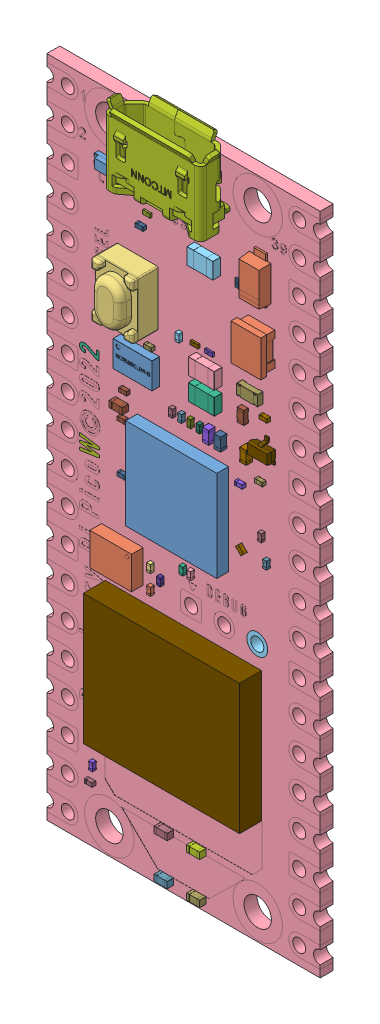
SolidWorks assembly RaspBerryPi Pico W, configuration Default. Lengths in mm.
Overall size (21 52.34 3.69).
82 component instances, 79 part files, 0 mates.
Components (placement in the parent):
- RaspBerryPi Pico W.step-1: RaspBerryPi Pico W.step [Default] at origin size (21 52.34 3.69)
  - PicoW v1.step-1: PicoW v1.step [Default] at (-10.5 -51 1.6) size (14.61 51.8 3.49)
    - Symbols.step-1: Symbols.step [Default] at origin size (14.61 51.8 3.49)
      - AVAGO_QSM.step-1: AVAGO_QSM.step [Default] at origin size (1.65 0.72 0.68)
      - BOURNS_SRN2512.step-1: BOURNS_SRN2512.step [Default] at origin size (2.29 2.79 1.22)
      - CAPC0603.step-1: CAPC0603.step [Default] at origin size (0.3 0.6 0.3)
      - CAPC0603 (1).step-1: CAPC0603 (1).step [Default] at origin size (0.6 0.3 0.3)
      - CAPC0603 (2).step-1: CAPC0603 (2).step [Default] at origin size (0.6 0.3 0.3)
      - CAPC0603 (3).step-1: CAPC0603 (3).step [Default] at origin size (0.6 0.3 0.3)
      - CAPC1005.step-1: CAPC1005.step [Default] at origin size (1 0.5 0.5)
      - CAPC1005 (1).step-1: CAPC1005 (1).step [Default] at origin size (0.5 1 0.5)
      - CAPC1005 (2).step-1: CAPC1005 (2).step [Default] at origin size (0.5 1 0.5)
      - CAPC1005 (3).step-1: CAPC1005 (3).step [Default] at origin size (0.5 1 0.5)
      - CAPC1005 (4).step-1: CAPC1005 (4).step [Default] at origin size (1 0.5 0.5)
      - CAPC1005 (5).step-1: CAPC1005 (5).step [Default] at origin size (1 0.5 0.5)
      - CAPC1005 (6).step-1: CAPC1005 (6).step [Default] at origin size (1 0.5 0.5)
      - CAPC1005 (7).step-1: CAPC1005 (7).step [Default] at origin size (1 0.5 0.5)
      - CAPC1005 (8).step-1: CAPC1005 (8).step [Default] at origin size (0.5 1 0.5)
      - CAPC1005 (9).step-1: CAPC1005 (9).step [Default] at origin size (1 0.5 0.5)
      - CAPC1005X55N.step-1: CAPC1005X55N.step [Default] at origin size (1 0.5 0.5)
      - CAPC1005X55N (1).step-1: CAPC1005X55N (1).step [Default] at origin size (0.5 1 0.5)
      - CAPC1005X55N (2).step-1: CAPC1005X55N (2).step [Default] at origin size (1 0.5 0.5)
      - CAPC1608X90N.step-1: CAPC1608X90N.step [Default] at origin size (1.6 0.8 0.8)
      - CAPC1608X90N (1).step-1: CAPC1608X90N (1).step [Default] at origin size (0.8 1.6 0.8)
      - CAPC2012.step-1: CAPC2012.step [Default] at origin size (2 1.25 0.6)
      - CAPC2012 (1).step-1: CAPC2012 (1).step [Default] at origin size (2 1.25 0.6)
      - CAPC2012 (2).step-1: CAPC2012 (2).step [Default] at origin size (2 1.25 0.6)
      - FCI_10103594-0001LF.step-1: FCI_10103594-0001LF.step [Default] at origin size (7.99 6.06 3.49)
      - M0603_PICO.step-1: M0603_PICO.step [Default] at origin size (0.6 0.3 0.3)
      - M0603_PICO (1).step-1: M0603_PICO (1).step [Default] at origin size (0.63 0.63 0.3)
      - M0603_PICO (2).step-1: M0603_PICO (2).step [Default] at origin size (0.6 0.3 0.3)
      - M0603_PICO (3).step-1: M0603_PICO (3).step [Default] at origin size (0.6 0.3 0.3)
      - M0603_PICO (4).step-1: M0603_PICO (4).step [Default] at origin size (0.6 0.3 0.3)
      - M0603_PICO (5).step-1: M0603_PICO (5).step [Default] at origin size (0.3 0.6 0.3)
      - M0603_PICO (6).step-1: M0603_PICO (6).step [Default] at origin size (0.3 0.6 0.3)
      - M0603_PICO (7).step-1: M0603_PICO (7).step [Default] at origin size (0.3 0.6 0.3)
      - M0603_PICO (8).step-1: M0603_PICO (8).step [Default] at origin size (0.3 0.6 0.3)
      - M0603_PICO (9).step-1: M0603_PICO (9).step [Default] at origin size (0.3 0.6 0.3)
      - M0603_PICO (10).step-1: M0603_PICO (10).step [Default] at origin size (0.3 0.6 0.3)
      - M0603_PICO (11).step-1: M0603_PICO (11).step [Default] at origin size (0.3 0.6 0.3)
      - M0603_PICO (12).step-1: M0603_PICO (12).step [Default] at origin size (0.3 0.6 0.3)
      - M0603_PICO (13).step-1: M0603_PICO (13).step [Default] at origin size (0.3 0.6 0.3)
      - M0603_PICO (14).step-1: M0603_PICO (14).step [Default] at origin size (0.3 0.6 0.3)
      - M0603_PICO (15).step-1: M0603_PICO (15).step [Default] at origin size (0.3 0.6 0.3)
      - M0603_PICO (16).step-1: M0603_PICO (16).step [Default] at origin size (0.3 0.6 0.3)
      - RESC0603.step-1: RESC0603.step [Default] at origin size (0.6 0.3 0.15)
      - RESC0603 (1).step-1: RESC0603 (1).step [Default] at origin size (0.6 0.3 0.15)
      - RESC0603 (2).step-1: RESC0603 (2).step [Default] at origin size (0.6 0.3 0.15)
      - RESC0603 (3).step-1: RESC0603 (3).step [Default] at origin size (0.3 0.6 0.15)
      - RESC1005.step-1: RESC1005.step [Default] at origin size (0.5 1 0.35)
      - RESC1608.step-1: RESC1608.step [Default] at origin size (1.6 0.8 0.45)
      - RF0603.step-1: RF0603.step [Default] at origin size (0.6 0.3 0.3)
      - RF0603 (1).step-1: RF0603 (1).step [Default] at origin size (0.63 0.63 0.3)
      - RF0603 (2).step-1: RF0603 (2).step [Default] at origin size (0.6 0.3 0.3)
      - RF0603 (3).step-1: RF0603 (3).step [Default] at origin size (0.3 0.6 0.3)
      - RF0603 (4).step-1: RF0603 (4).step [Default] at origin size (0.3 0.6 0.3)
      - RF_SHIELD_PICOW.step-1: RF_SHIELD_PICOW.step [Default] at origin size (12 10 1.7)
      - RPI_RP2040.step-1: RPI_RP2040.step [Default] at origin size (7 7 0.9)
      - SOD123FL.step-1: SOD123FL.step [Default] at origin size (1.65 3.6 0.98)
      - SONY0603.step-1: SONY0603.step [Default] at origin size (0.3 0.6 0.3)
      - SONY0603 (1).step-1: SONY0603 (1).step [Default] at origin size (0.6 0.3 0.3)
      - SONY0603 (2).step-1: SONY0603 (2).step [Default] at origin size (0.63 0.63 0.3)
      - SONY0603 (3).step-1: SONY0603 (3).step [Default] at origin size (0.3 0.6 0.3)
      - SONY0603 (4).step-1: SONY0603 (4).step [Default] at origin size (0.6 0.3 0.3)
      - SONY0603 (5).step-1: SONY0603 (5).step [Default] at origin size (0.3 0.6 0.3)
      - SONY0603 (6).step-1: SONY0603 (6).step [Default] at origin size (0.6 0.3 0.3)
      - SONY0603 (7).step-1: SONY0603 (7).step [Default] at origin size (0.6 0.3 0.3)
      - SONY0603 (8).step-1: SONY0603 (8).step [Default] at origin size (0.6 0.3 0.3)
      - SONY0603 (9).step-1: SONY0603 (9).step [Default] at origin size (0.6 0.3 0.3)
      - SONY0603 (10).step-1: SONY0603 (10).step [Default] at origin size (0.3 0.6 0.3)
      - SONY0603 (11).step-1: SONY0603 (11).step [Default] at origin size (0.3 0.6 0.3)
      - SONY0603 (12).step-1: SONY0603 (12).step [Default] at origin size (0.6 0.3 0.3)
      - SONY0603 (13).step-1: SONY0603 (13).step [Default] at origin size (0.3 0.6 0.3)
      - SONY0603 (14).step-1: SONY0603 (14).step [Default] at origin size (0.3 0.6 0.3)
      - SOT50P160X90-3N.step-1: SOT50P160X90-3N.step [Default] at origin size (1.6 1.6 0.8)
      - USON_2X3MM.step-1: USON_2X3MM.step [Default] at origin size (3 2 0.6)
      - XTAL320X250X100.step-1: XTAL320X250X100.step [Default] at origin size (3.2 2.5 0.92)
  - BOOTSEL v3.step-1: BOOTSEL v3.step [Default] at (-3.55 -9.9 1.6) size (3.24 4.29 2.5)
  - RaspBerryPi Pico_CircuitBoard_logo v15.step-1: RaspBerryPi Pico_CircuitBoard_logo v15.step [Default] at (0.0013 0.005 0.0066) size (21 51 1.01)
  - RaspBerryPi Pico W.step-1: RaspBerryPi Pico W.step [Default] at origin size (1.6 1.6 1)
  - RaspBerryPi Pico W-0.step-1: RaspBerryPi Pico W-0.step [Default] at origin size (1.51 0.64 0.01)
  - RaspBerryPi Pico W-1.step-1: RaspBerryPi Pico W-1.step [Default] at origin size (1.5 1.18 0.01)
